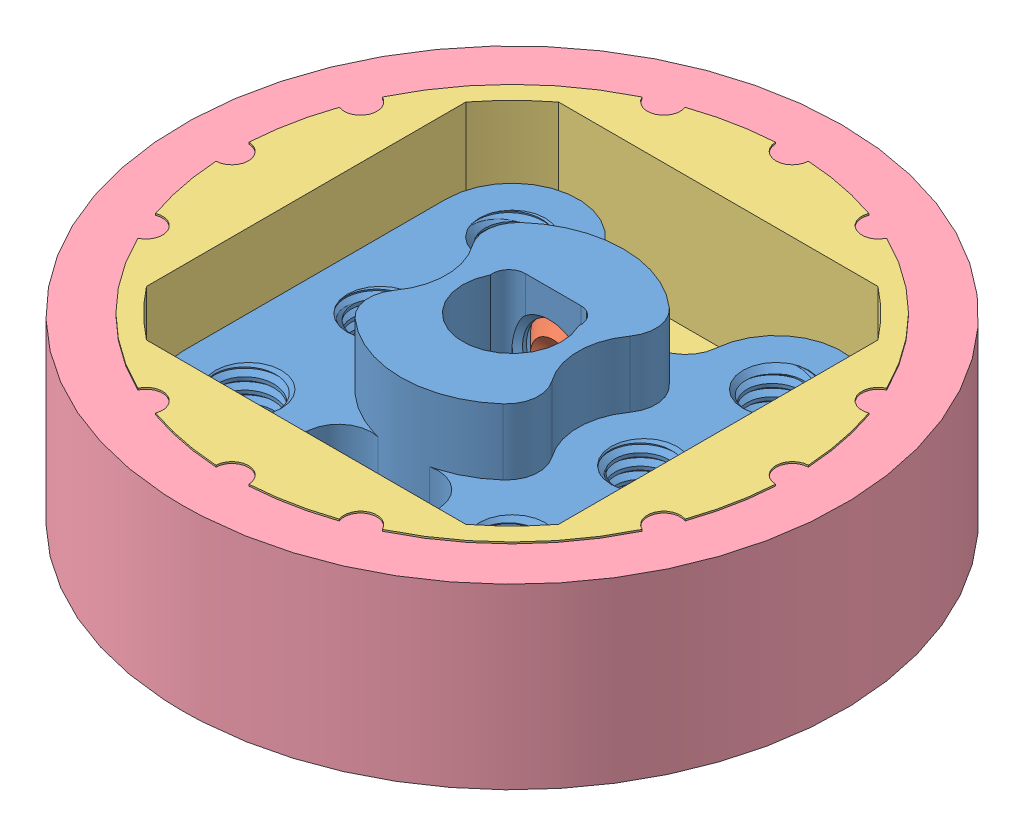
SolidWorks assembly wheel-40mm-gobilda-hub, configuration Default. Lengths in mm.
Overall size (40 11 40).
5 component instances, 4 part files, 5 mates.
Components (placement in the parent):
- 1308-0016-1006 assembly-1: 1308-0016-1006 assembly [Default] at (-6.1581 7.9163 -4.9236) size (24 8.14 24)
  - 1308-0016-1006-1: 1308-0016-1006 [Default] at (6.1581 -15.9163 4.9236) size (24 8.14 24)
  - 2806-0005-0004_91390A117-1: 2806-0005-0004_91390A117 [Default] at (6.1581 -11.9163 0.032) x (-0.598774 -0.800918 0) z (0 0 -1) size (5.13 5 4.14)
- rim^wheel-40mm-gobilda-hub-1: rim^wheel-40mm-gobilda-hub [Default] at origin size (34 11 34) (virtual)
- tire^wheel-40mm-gobilda-hub-1: tire^wheel-40mm-gobilda-hub [Default] at origin size (40 10.8 40) (virtual)
Mates (geometry in assembly coordinates):
- Coincident1: coordinate: point of rim^wheel-40mm-gobilda-hub-1
- Coincident4: coincident aligned: plane of 1308-0016-1006 assembly-1 through (-6.1581 0 -4.9236) normal (0 1 0)
- Coincident5: coincident: line of 1308-0016-1006 assembly-1 through (8 0 -8) axis (0 0 1)
- Coincident6: coincident: line of 1308-0016-1006 assembly-1 through (8 0 -8) axis (0 0 1)
- Coincident7: coordinate: unknown of tire^wheel-40mm-gobilda-hub-1
